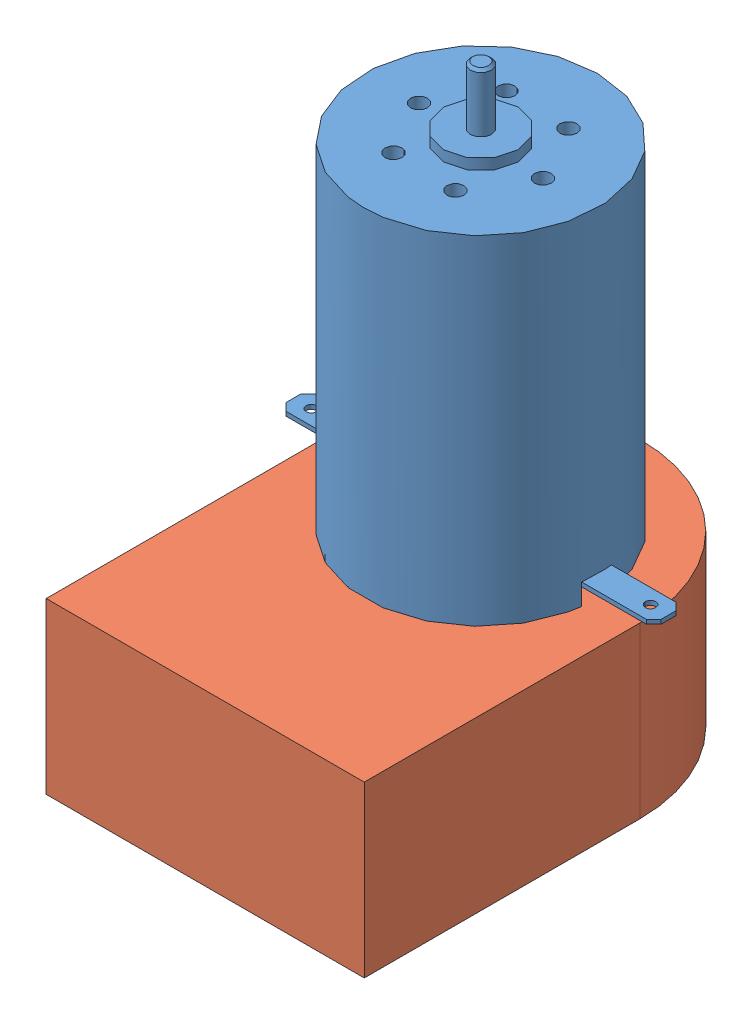
SolidWorks assembly Codeur+Moteur, configuration Défaut. Lengths in mm.
Overall size (35.4 54.4 41).
2 component instances, 2 part files, 2 mates.
Components (placement in the parent):
- AMAX_22_CLL-1: AMAX_22_CLL [Default] at (-12.6505 -10.9283 0) size (35.4 54.4 22)
- HEDS5540-1: HEDS5540 [Défaut] at (-27.6505 -26.9283 26) size (30 16 41)
Mates (geometry in assembly coordinates):
- Coïncidente1: coincident anti-aligned: plane of AMAX_22_CLL-1 through (-12.6505 -13.4283 0) normal (0 -1 0); plane of HEDS5540-1 through (-12.6505 -13.4283 0) normal (0 1 0)
- Coïncidente2: coincident anti-aligned: circle of AMAX_22_CLL-1; circle of HEDS5540-1
